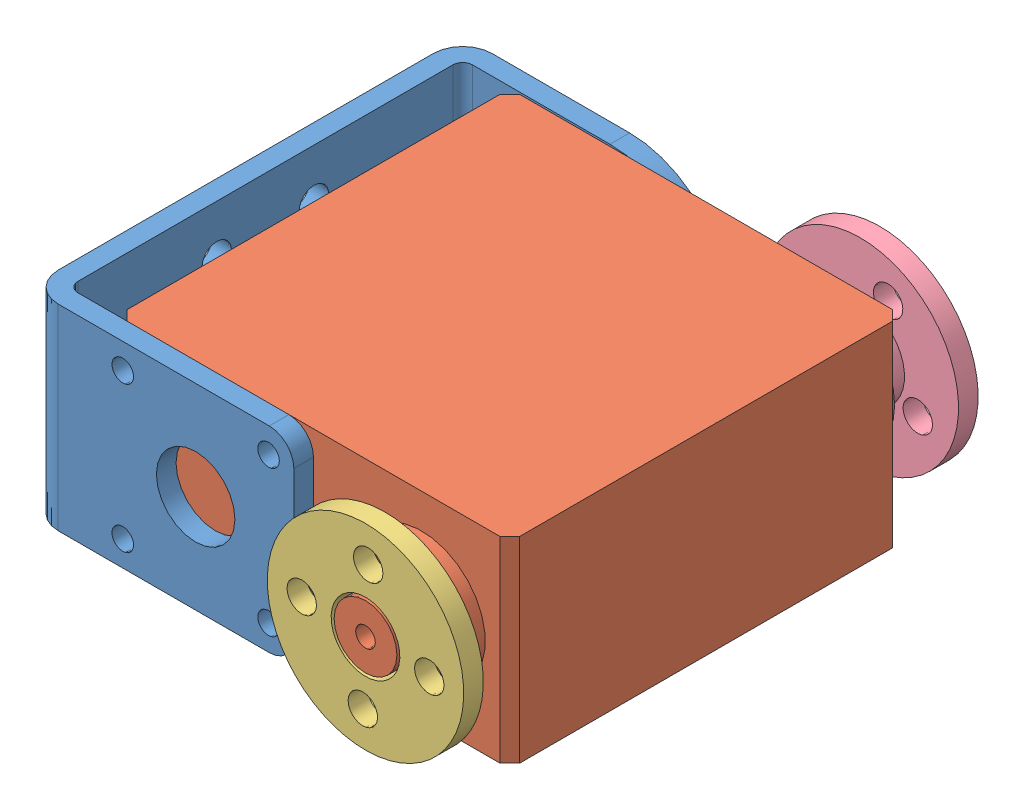
SolidWorks assembly servo_asm, configuration 默认. Lengths in mm.
Overall size (51.36 26.71 52.4).
4 component instances, 4 part files, 7 mates.
Components (placement in the parent):
- ZJ-DUAN-1: ZJ-DUAN [默认] at (575.5682 225.0277 280.3388) x (-1 0 0) z (0 -1 0) size (27 44.2 20)
- 舵机-1: 舵机 [默认] at (546.9248 215.0277 274.2891) x (-1 0 0) z (0 0 -1) size (40 20 48.7)
- 无齿盘-1: 无齿盘 [默认] at (596.5682 225.0277 306.1388) x (-0.041997 -0.999118 0) z (0.999118 -0.041997 0) size (20 3 20)
- 有齿盘-1: 有齿盘 [默认] at (596.5682 225.0277 253.7388) x (0.900229 -0.435417 0) z (-0.435417 -0.900229 0) size (20 4.2 20)
Mates (geometry in assembly coordinates):
- 重合5: coincident anti-aligned: plane of ZJ-DUAN-1 through (560.5682 235.0277 300.4388) normal (0 0 -1); plane of 舵机-1 through (604.5682 235.0277 300.4388) normal (0 0 1)
- 重合6: coincident aligned: plane of ZJ-DUAN-1 through (575.5682 215.0277 280.3388) normal (0 -1 0); plane of 舵机-1 through (546.9248 215.0277 274.2891) normal (0 -1 0)
- 距离1: distance = 5 mm anti-aligned: plane of ZJ-DUAN-1 through (560.5682 235.0277 260.2388) normal (1 0 0); plane of 舵机-1 through (565.5682 235.0277 299.4388) normal (-1 0 0)
- 距离2: distance = 1 mm anti-aligned: plane of 无齿盘-1 through (596.5682 225.0277 303.1388) normal (0 0 -1); plane of 舵机-1 through (596.5682 225.0277 302.1388) normal (0 0 1)
- 同心1: concentric anti-aligned: cylinder of 舵机-1 through (596.5682 225.0277 306.1388) axis (0 0 -1) radius 3.2; cylinder of 无齿盘-1 through (596.5682 225.0277 303.1388) axis (0 0 1) radius 3.5
- 同心2: concentric aligned: cylinder of 舵机-1 through (596.5682 225.0277 257.4388) axis (0 0 1) radius 2.5; cylinder of 有齿盘-1 through (596.5682 225.0277 255.7388) axis (0 0 1) radius 2.5
- 距离5: distance = 0.8 mm anti-aligned: plane of 舵机-1 through (596.5682 225.0277 258.7388) normal (0 0 -1); plane of 有齿盘-1 through (596.5682 225.0277 257.9388) normal (0 0 1)
